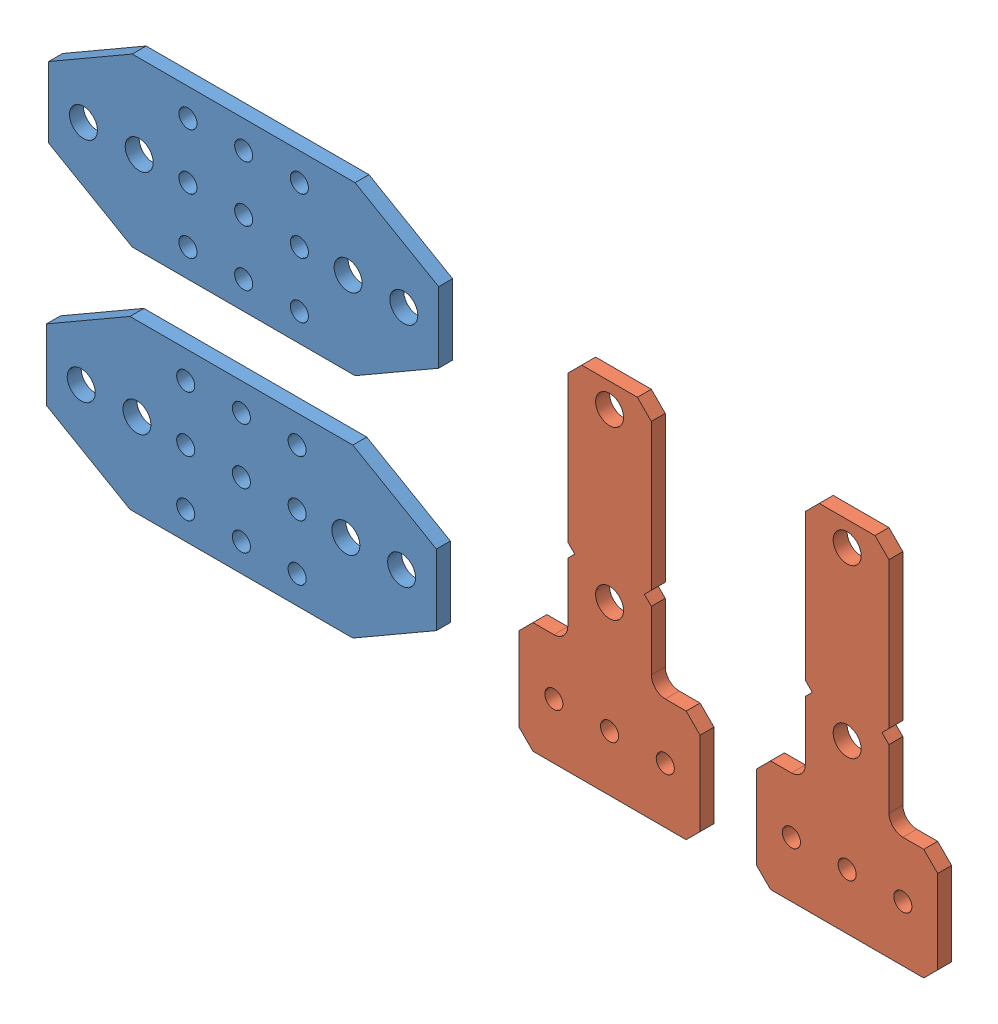
SolidWorks assembly 217-4399-STEP-20150113, configuration Default. Lengths in mm.
Overall size (203.17 92.19 3.18).
4 component instances, 2 part files, 0 mates.
Components (placement in the parent):
- 217-4399-001 Rev2-1: 217-4399-001 Rev2 [Default] at origin size (88.9 38.1 3.17)
- 217-4399-005 Rev2-1: 217-4399-005 Rev2 [Default] at (83.9223 20.0298 0) size (41.28 81.79 3.18)
- 217-4399-001 Rev2-2: 217-4399-001 Rev2 [Default] at (0.511 52.0521 0) size (88.9 38.1 3.17)
- 217-4399-005 Rev2-2: 217-4399-005 Rev2 [Default] at (138.078 19.8098 0) size (41.28 81.79 3.18)
